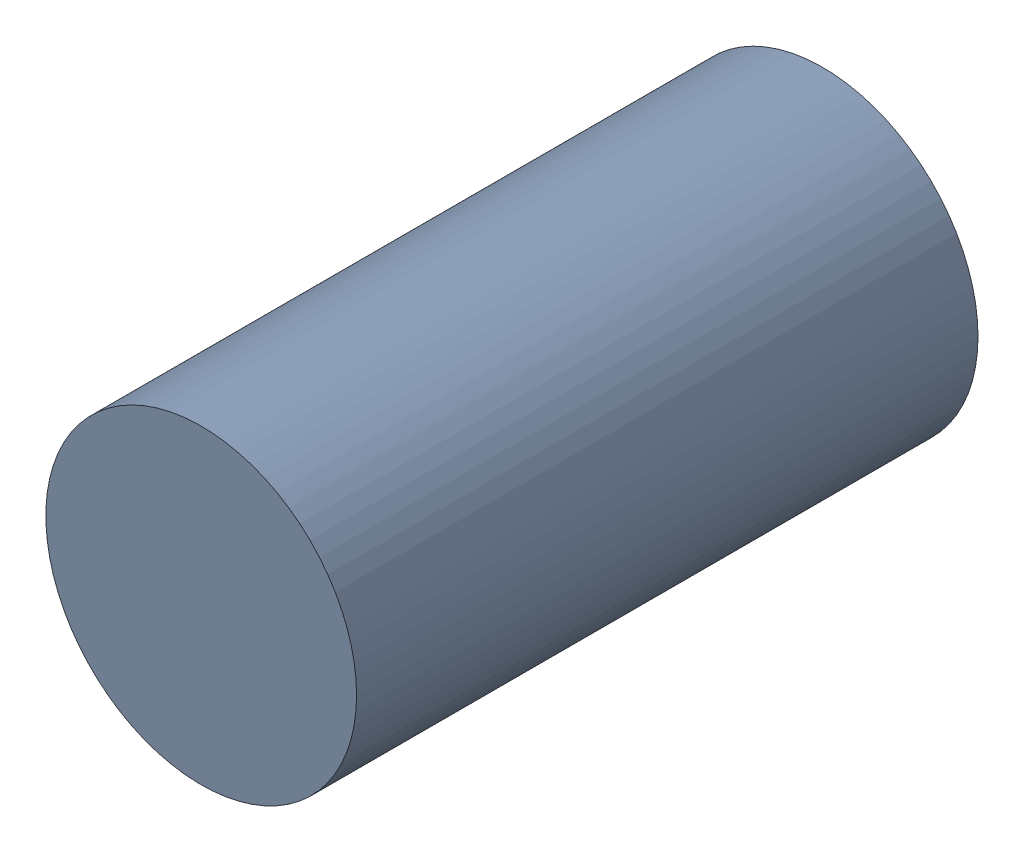
SolidWorks assembly MH6_1.step, configuration Default. Lengths in mm.
Overall size (1 1 2).
2 component instances, 1 part files, 0 mates.
Components (placement in the parent):
- 9228463120_1.step-11: 9228463120_1.step [Default] at (500.126 316.992 -1.5) size (1 1 2)
  - Cylinder_1.step-98: Cylinder_1.step [Default] at origin size (1 1 2)
